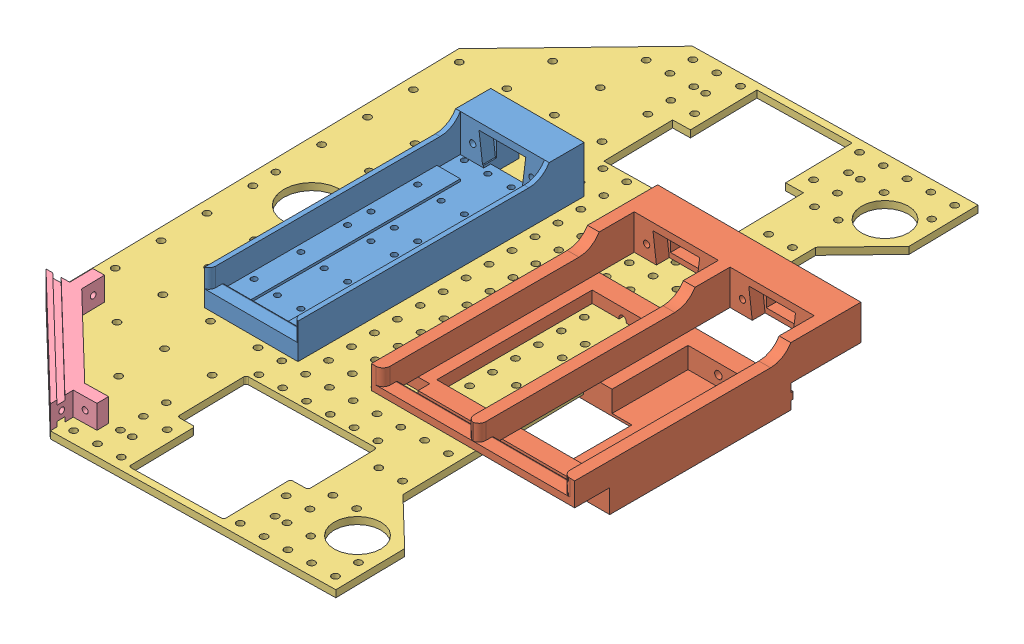
SolidWorks assembly Assem1, configuration Default. Lengths in mm.
Overall size (200.91 25 283.09).
4 component instances, 4 part files, 7 mates.
Components (placement in the parent):
- BatteriesBottomRackSmallRobot-1: BatteriesBottomRackSmallRobot [Default] at (0.1077 66.0409 41.8802) size (40 20 122.5)
- BatteriesBottomRack-1: BatteriesBottomRack [Default] at (95.0286 61.0409 10.6302) size (87 25 122.5)
- Plate-SmallRobot-Lower-3mm-3-1: Plate-SmallRobot-Lower-3mm-3 [Default] at (50.1889 66.0409 40.6792) x (0.99983 0 -0.018464) z (0 -1 0) size (170 280 3)
- SmallRobotWindowCorner50x50x45deg-1: SmallRobotWindowCorner50x50x45deg [Default] at (-32.6732 71.0409 157.2291) x (0.99983 0 -0.018464) z (0 -1 0) size (60 60 10)
Mates (geometry in assembly coordinates):
- Coincident1: coincident aligned: plane of BatteriesBottomRackSmallRobot-1 through (0.1077 66.0409 -19.3698) normal (0 0 -1); plane of BatteriesBottomRack-1 through (95.0286 61.0409 -19.3698) normal (0 0 -1)
- Coincident2: coincident aligned: plane of BatteriesBottomRackSmallRobot-1 through (20.1077 86.0409 -19.3698) normal (0 1 0); plane of BatteriesBottomRack-1 through (138.5286 86.0409 -4.3698) normal (0 1 0)
- Coincident3: coincident anti-aligned: plane of BatteriesBottomRackSmallRobot-1 through (20.1077 66.0409 103.1302) normal (0 -1 0); plane of Plate-SmallRobot-Lower-3mm-3-1 through (50.1889 66.0409 40.6792) normal (0 1 0)
- Concentric1: concentric aligned: cylinder of BatteriesBottomRackSmallRobot-1 through (-14.8923 86.0409 36.8802) axis (0 -1 0) radius 1.25; cylinder of Plate-SmallRobot-Lower-3mm-3-1 through (-14.8923 66.0409 36.8802) axis (0 -1 0) radius 1.5
- Coincident4: coincident anti-aligned: plane of Plate-SmallRobot-Lower-3mm-3-1 through (50.1889 66.0409 40.6792) normal (0 1 0); plane of SmallRobotWindowCorner50x50x45deg-1 through (-32.6732 66.0409 157.2291) normal (0 -1 0)
- Coincident5: coincident aligned: plane of Plate-SmallRobot-Lower-3mm-3-1 through (-7.2159 63.0409 181.7632) normal (-0.69393 0 0.720042); plane of SmallRobotWindowCorner50x50x45deg-1 through (-58.1306 66.0409 132.6949) normal (-0.69393 0 0.720042)
- Coincident6: coincident: point of Plate-SmallRobot-Lower-3mm-3-1; point of SmallRobotWindowCorner50x50x45deg-1
